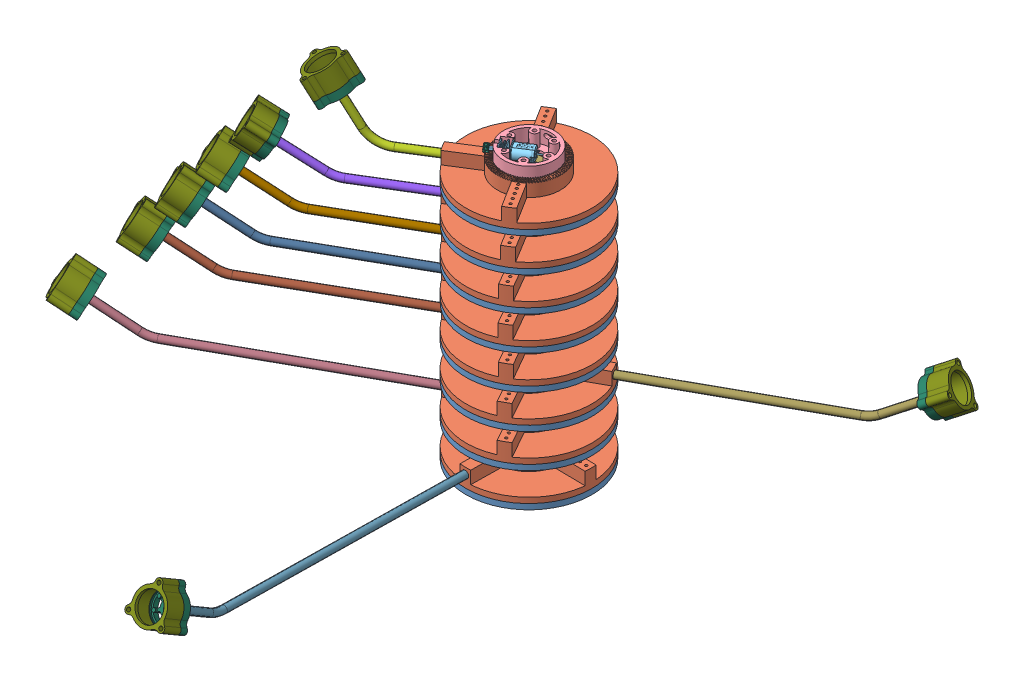
SolidWorks assembly full_assem, configuration Default. Lengths in mm.
Overall size (555.36 303.27 514.32).
88 component instances, 16 part files, 48 mates.
Components (placement in the parent):
- new_assem-1: new_assem [Default] at (2.9813 -21.7891 5.7568) size (116.84 31 116.84)
  - lower_platter-1: lower_platter [Default] at (-7.5252 -0.5831 4.7068) size (115 9 115)
  - upper_platter-1: upper_platter [Default] at (-7.5252 15.9169 4.7068) x (0.99987 0 0.016145) z (0 -1 0) size (115 115 17.53)
  - lower_platter_splitter-1: lower_platter_splitter [Default] at (-7.5252 9.4169 4.7068) x (1 0 0.000905) z (0 -1 0) size (46.67 46.67 6)
  - lower_platter_closeout-1: lower_platter_closeout [Default] at (-7.5252 12.9169 4.7068) x (1 0 0.000905) z (0 -1 0) size (46.67 46.67 16)
  - pololu_micro_motor-1: pololu_micro_motor [Default] at (-7.5351 19.4169 15.7068) x (1 0 0.000905) z (-0.000905 0 1) size (12.01 10.08 40.2)
  - lil_gear-1: lil_gear [Default] at (-7.549 19.4169 30.9948) x (1 0 0.000905) z (-0.000905 0 1) size (6.61 6.52 3.75)
- new_assem-2: new_assem [Default] at (3.2949 9.2109 14.6272) x (0.5 0 0.866025) z (-0.866025 0 0.5) size (116.84 31 116.84)
  - lower_platter-1: lower_platter [Default] at (-7.5252 -0.5831 4.7068) size (115 9 115)
  - upper_platter-1: upper_platter [Default] at (-7.5252 15.9169 4.7068) x (0.99987 0 0.016145) z (0 -1 0) size (115 115 17.53)
  - lower_platter_splitter-1: lower_platter_splitter [Default] at (-7.5252 9.4169 4.7068) x (1 0 0.000905) z (0 -1 0) size (46.67 46.67 6)
  - lower_platter_closeout-1: lower_platter_closeout [Default] at (-7.5252 12.9169 4.7068) x (1 0 0.000905) z (0 -1 0) size (46.67 46.67 16)
  - pololu_micro_motor-1: pololu_micro_motor [Default] at (-7.5351 19.4169 15.7068) x (1 0 0.000905) z (-0.000905 0 1) size (12.01 10.08 40.2)
  - lil_gear-1: lil_gear [Default] at (-7.549 19.4169 30.9948) x (1 0 0.000905) z (-0.000905 0 1) size (6.61 6.52 3.75)
- new_assem-3: new_assem [Default] at (3.35 71.2109 14.5216) x (0.511572 0 0.85924) z (-0.85924 0 0.511572) size (116.84 31 116.84)
  - lower_platter-1: lower_platter [Default] at (-7.5252 -0.5831 4.7068) size (115 9 115)
  - upper_platter-1: upper_platter [Default] at (-7.5252 15.9169 4.7068) x (0.99987 0 0.016145) z (0 -1 0) size (115 115 17.53)
  - lower_platter_splitter-1: lower_platter_splitter [Default] at (-7.5252 9.4169 4.7068) x (1 0 0.000905) z (0 -1 0) size (46.67 46.67 6)
  - lower_platter_closeout-1: lower_platter_closeout [Default] at (-7.5252 12.9169 4.7068) x (1 0 0.000905) z (0 -1 0) size (46.67 46.67 16)
  - pololu_micro_motor-1: pololu_micro_motor [Default] at (-7.5351 19.4169 15.7068) x (1 0 0.000905) z (-0.000905 0 1) size (12.01 10.08 40.2)
  - lil_gear-1: lil_gear [Default] at (-7.549 19.4169 30.9948) x (1 0 0.000905) z (-0.000905 0 1) size (6.61 6.52 3.75)
- new_assem-4: new_assem [Default] at (-12.3789 40.2109 6.2929) x (-0.499216 0 -0.866478) z (0.866478 0 -0.499216) size (116.84 31 116.84)
  - lower_platter-1: lower_platter [Default] at (-7.5252 -0.5831 4.7068) size (115 9 115)
  - upper_platter-1: upper_platter [Default] at (-7.5252 15.9169 4.7068) x (0.99987 0 0.016145) z (0 -1 0) size (115 115 17.53)
  - lower_platter_splitter-1: lower_platter_splitter [Default] at (-7.5252 9.4169 4.7068) x (1 0 0.000905) z (0 -1 0) size (46.67 46.67 6)
  - lower_platter_closeout-1: lower_platter_closeout [Default] at (-7.5252 12.9169 4.7068) x (1 0 0.000905) z (0 -1 0) size (46.67 46.67 16)
  - pololu_micro_motor-1: pololu_micro_motor [Default] at (-7.5351 19.4169 15.7068) x (1 0 0.000905) z (-0.000905 0 1) size (12.01 10.08 40.2)
  - lil_gear-1: lil_gear [Default] at (-7.549 19.4169 30.9948) x (1 0 0.000905) z (-0.000905 0 1) size (6.61 6.52 3.75)
- new_assem-5: new_assem [Default] at (3.5046 195.2109 14.2057) x (0.545217 0 0.838295) z (-0.838295 0 0.545217) size (116.84 31 116.84)
  - lower_platter-1: lower_platter [Default] at (-7.5252 -0.5831 4.7068) size (115 9 115)
  - upper_platter-1: upper_platter [Default] at (-7.5252 15.9169 4.7068) x (0.99987 0 0.016145) z (0 -1 0) size (115 115 17.53)
  - lower_platter_splitter-1: lower_platter_splitter [Default] at (-7.5252 9.4169 4.7068) x (1 0 0.000905) z (0 -1 0) size (46.67 46.67 6)
  - lower_platter_closeout-1: lower_platter_closeout [Default] at (-7.5252 12.9169 4.7068) x (1 0 0.000905) z (0 -1 0) size (46.67 46.67 16)
  - pololu_micro_motor-1: pololu_micro_motor [Default] at (-7.5351 19.4169 15.7068) x (1 0 0.000905) z (-0.000905 0 1) size (12.01 10.08 40.2)
  - lil_gear-1: lil_gear [Default] at (-7.549 19.4169 30.9948) x (1 0 0.000905) z (-0.000905 0 1) size (6.61 6.52 3.75)
- new_assem-6: new_assem [Default] at (3.365 133.2109 14.4925) x (0.514741 0 0.857346) z (-0.857346 0 0.514741) size (116.84 31 116.84)
  - lower_platter-1: lower_platter [Default] at (-7.5252 -0.5831 4.7068) size (115 9 115)
  - upper_platter-1: upper_platter [Default] at (-7.5252 15.9169 4.7068) x (0.99987 0 0.016145) z (0 -1 0) size (115 115 17.53)
  - lower_platter_splitter-1: lower_platter_splitter [Default] at (-7.5252 9.4169 4.7068) x (1 0 0.000905) z (0 -1 0) size (46.67 46.67 6)
  - lower_platter_closeout-1: lower_platter_closeout [Default] at (-7.5252 12.9169 4.7068) x (1 0 0.000905) z (0 -1 0) size (46.67 46.67 16)
  - pololu_micro_motor-1: pololu_micro_motor [Default] at (-7.5351 19.4169 15.7068) x (1 0 0.000905) z (-0.000905 0 1) size (12.01 10.08 40.2)
  - lil_gear-1: lil_gear [Default] at (-7.549 19.4169 30.9948) x (1 0 0.000905) z (-0.000905 0 1) size (6.61 6.52 3.75)
- new_assem-7: new_assem [Default] at (3.3308 102.2109 14.5589) x (0.50751 0 0.861646) z (-0.861646 0 0.50751) size (116.84 31 116.84)
  - lower_platter-1: lower_platter [Default] at (-7.5252 -0.5831 4.7068) size (115 9 115)
  - upper_platter-1: upper_platter [Default] at (-7.5252 15.9169 4.7068) x (0.99987 0 0.016145) z (0 -1 0) size (115 115 17.53)
  - lower_platter_splitter-1: lower_platter_splitter [Default] at (-7.5252 9.4169 4.7068) x (1 0 0.000905) z (0 -1 0) size (46.67 46.67 6)
  - lower_platter_closeout-1: lower_platter_closeout [Default] at (-7.5252 12.9169 4.7068) x (1 0 0.000905) z (0 -1 0) size (46.67 46.67 16)
  - pololu_micro_motor-1: pololu_micro_motor [Default] at (-7.5351 19.4169 15.7068) x (1 0 0.000905) z (-0.000905 0 1) size (12.01 10.08 40.2)
  - lil_gear-1: lil_gear [Default] at (-7.549 19.4169 30.9948) x (1 0 0.000905) z (-0.000905 0 1) size (6.61 6.52 3.75)
- new_assem-8: new_assem [Default] at (3.4595 164.2109 14.3012) x (0.535204 0 0.844723) z (-0.844723 0 0.535204) size (116.84 31 116.84)
  - lower_platter-1: lower_platter [Default] at (-7.5252 -0.5831 4.7068) size (115 9 115)
  - upper_platter-1: upper_platter [Default] at (-7.5252 15.9169 4.7068) x (0.99987 0 0.016145) z (0 -1 0) size (115 115 17.53)
  - lower_platter_splitter-1: lower_platter_splitter [Default] at (-7.5252 9.4169 4.7068) x (1 0 0.000905) z (0 -1 0) size (46.67 46.67 6)
  - lower_platter_closeout-1: lower_platter_closeout [Default] at (-7.5252 12.9169 4.7068) x (1 0 0.000905) z (0 -1 0) size (46.67 46.67 16)
  - pololu_micro_motor-1: pololu_micro_motor [Default] at (-7.5351 19.4169 15.7068) x (1 0 0.000905) z (-0.000905 0 1) size (12.01 10.08 40.2)
  - lil_gear-1: lil_gear [Default] at (-7.549 19.4169 30.9948) x (1 0 0.000905) z (-0.000905 0 1) size (6.61 6.52 3.75)
- arm0-1: arm0 [Default] at (-38.4234 205.3777 31.7281) x (0.531611 0 0.846988) z (0.846988 0 -0.531611) size (6.35 48.76 91.65)
- arm1-1: arm1 [Default] at (-38.674 174.3777 31.3234) x (0.521496 0 0.853254) z (0.853254 0 -0.521496) size (6.35 31.32 134.48)
- arm2-1: arm2 [Default] at (-39.1657 143.3777 30.4969) x (0.500832 0 0.865544) z (0.865544 0 -0.500832) size (6.35 31.32 159.88)
- arm3-1: arm3 [Default] at (-39.333 112.3777 30.2049) x (0.493533 0 0.869727) z (0.869727 0 -0.493533) size (6.35 31.32 185.28)
- arm4-1: arm4 [Default] at (-39.2394 81.3777 30.3689) x (0.497633 0 0.867388) z (0.867388 0 -0.497633) size (6.35 31.32 210.68)
- arm5-1: arm5 [Default] at (30.4331 50.3777 -8.9429) x (-0.485161 0 -0.874425) z (-0.874425 0 0.485161) size (6.35 31.32 236.08)
- arm6-1: arm6 [Default] at (-39.5033 19.3777 29.9017) x (0.485953 0 0.873985) z (0.873985 0 -0.485953) size (6.35 31.32 261.48)
- arm7-1: arm7 [Default] at (-5.1897 -11.6223 50.4584) x (0.99987 0 0.016145) z (0.016145 0 -0.99987) size (6.35 31.32 286.88)
- light_housing-1: light_housing [Default] at (-131.0667 165.473 103.0819) x (0.617031 0.771417 0.155526) z (-0.73894 0.5 0.451629) size (36.38 35.5 23.75)
  - light_housing_1-1: light_housing_1 [Default] at (13.124 21.3419 26.5612) size (36.38 35.5 7)
  - light_housing_2-1: light_housing_2 [Default] at (13.124 21.3419 47.3112) x (-1 0 0) z (0 0 -1) size (36.38 35.5 17)
- light_housing-2: light_housing [Default] at (-122.9785 211.3397 69.4133) x (0.53478 0.002163 0.844989) z (-0.423494 0.866025 0.265806) size (36.38 35.5 23.75)
  - light_housing_1-1: light_housing_1 [Default] at (13.124 21.3419 26.5612) size (36.38 35.5 7)
  - light_housing_2-1: light_housing_2 [Default] at (13.124 21.3419 47.3112) x (-1 0 0) z (0 0 -1) size (36.38 35.5 17)
- light_housing-3: light_housing [Default] at (-167.2651 143.2122 96.7592) x (-0.65725 -0.598271 -0.45836) z (-0.753206 0.5 0.427412) size (36.38 35.5 23.75)
  - light_housing_1-1: light_housing_1 [Default] at (13.124 21.3419 26.5612) size (36.38 35.5 7)
  - light_housing_2-1: light_housing_2 [Default] at (13.124 21.3419 47.3112) x (-1 0 0) z (0 0 -1) size (36.38 35.5 17)
- light_housing-4: light_housing [Default] at (-256.2752 7.9147 143.653) x (0.596799 0.266353 0.756893) z (-0.756893 0.5 0.420847) size (36.38 35.5 23.75)
  - light_housing_1-1: light_housing_1 [Default] at (13.124 21.3419 26.5612) size (36.38 35.5 7)
  - light_housing_2-1: light_housing_2 [Default] at (13.124 21.3419 47.3112) x (-1 0 0) z (0 0 -1) size (36.38 35.5 17)
- light_housing-5: light_housing [Default] at (225.3721 56.4269 -88.8401) x (0.010993 -0.653005 -0.757274) z (0.757274 0.5 -0.420162) size (36.38 35.5 23.75)
  - light_housing_1-1: light_housing_1 [Default] at (13.124 21.3419 26.5612) size (36.38 35.5 7)
  - light_housing_2-1: light_housing_2 [Default] at (13.124 21.3419 47.3112) x (-1 0 0) z (0 0 -1) size (36.38 35.5 17)
- light_housing-6: light_housing [Default] at (-213.4227 76.1178 109.2772) x (0.367319 -0.225837 0.902261) z (-0.75118 0.5 0.430963) size (36.38 35.5 23.75)
  - light_housing_1-1: light_housing_1 [Default] at (13.124 21.3419 26.5612) size (36.38 35.5 7)
  - light_housing_2-1: light_housing_2 [Default] at (13.124 21.3419 47.3112) x (-1 0 0) z (0 0 -1) size (36.38 35.5 17)
- light_housing-7: light_housing [Default] at (-22.557 -20.5345 318.8735) x (0.999895 0.003747 0.013982) z (-0.013982 0.5 0.865913) size (36.38 35.5 23.75)
  - light_housing_1-1: light_housing_1 [Default] at (13.124 21.3419 26.5612) size (36.38 35.5 7)
  - light_housing_2-1: light_housing_2 [Default] at (13.124 21.3419 47.3112) x (-1 0 0) z (0 0 -1) size (36.38 35.5 17)
- light_housing-8: light_housing [Default] at (-166.7816 132.4201 95.1575) x (0.585857 0.196204 0.786305) z (-0.749583 0.5 0.433733) size (36.38 35.5 23.75)
  - light_housing_1-1: light_housing_1 [Default] at (13.124 21.3419 26.5612) size (36.38 35.5 7)
  - light_housing_2-1: light_housing_2 [Default] at (13.124 21.3419 47.3112) x (-1 0 0) z (0 0 -1) size (36.38 35.5 17)
Mates (geometry in assembly coordinates):
- Coincident1: coincident anti-aligned: plane of new_assem-1/lower_platter_closeout-1 through (-4.5439 3.6277 10.4636) normal (0 1 0); plane of new_assem-2/lower_platter-1 through (-4.5439 3.6277 10.4636) normal (0 -1 0)
- Concentric1: concentric aligned: cylinder of new_assem-1/lower_platter-1 through (3.9986 -27.3723 25.2596) axis (0 1 0) radius 1.625; cylinder of new_assem-2/lower_platter-1 through (3.9986 3.6277 25.2596) axis (0 1 0) radius 1.625
- Concentric3: concentric aligned: cylinder of new_assem-1/lower_platter-1 through (-21.6289 -27.3723 10.4636) axis (0 1 0) radius 1.625; cylinder of new_assem-2/lower_platter-1 through (-21.6289 3.6277 10.4636) axis (0 1 0) radius 1.625
- Coincident2: coincident anti-aligned: plane of new_assem-2/lower_platter_closeout-1 through (-4.5439 34.6277 10.4636) normal (0 1 0); plane of new_assem-4/lower_platter-1 through (-4.5439 34.6277 10.4636) normal (0 -1 0)
- Concentric4: concentric anti-aligned: cylinder of new_assem-2/lower_platter_closeout-1 through (12.5411 34.6277 10.4791) axis (0 -1 0) radius 1.625; cylinder of new_assem-4/lower_platter-1 through (12.5411 34.6277 10.4791) axis (0 1 0) radius 1.625
- Concentric5: concentric aligned: cylinder of new_assem-2/upper_platter-1 through (-4.5439 13.6277 10.4636) axis (0 -1 0) radius 57.5; cylinder of new_assem-4/upper_platter-1 through (-4.5439 44.6277 10.4636) axis (0 -1 0) radius 57.5
- Coincident3: coincident anti-aligned: plane of new_assem-3/lower_platter-1 through (-4.5439 65.6277 10.4636) normal (0 -1 0); plane of new_assem-4/lower_platter_closeout-1 through (-4.5439 65.6277 10.4636) normal (0 1 0)
- Concentric6: concentric aligned: cylinder of new_assem-3/upper_platter-1 through (-4.5439 75.6277 10.4636) axis (0 -1 0) radius 57.5; cylinder of new_assem-4/upper_platter-1 through (-4.5439 44.6277 10.4636) axis (0 -1 0) radius 57.5
- Coincident4: coincident anti-aligned: plane of new_assem-3/lower_platter_closeout-1 through (-4.5439 96.6277 10.4636) normal (0 1 0); plane of new_assem-7/lower_platter-1 through (-4.5439 96.6277 10.4636) normal (0 -1 0)
- Concentric7: concentric aligned: cylinder of new_assem-3/lower_platter_closeout-1 through (-4.5439 80.6277 10.4636) axis (0 1 0) radius 13.335; cylinder of new_assem-7/lower_platter_closeout-1 through (-4.5439 111.6277 10.4636) axis (0 1 0) radius 13.335
- Coincident5: coincident anti-aligned: plane of new_assem-6/lower_platter-1 through (-4.5439 127.6277 10.4636) normal (0 -1 0); plane of new_assem-7/lower_platter_closeout-1 through (-4.5439 127.6277 10.4636) normal (0 1 0)
- Concentric8: concentric aligned: cylinder of new_assem-6/upper_platter-1 through (-4.5439 137.6277 10.4636) axis (0 -1 0) radius 57.5; cylinder of new_assem-7/upper_platter-1 through (-4.5439 106.6277 10.4636) axis (0 -1 0) radius 57.5
- Coincident6: coincident anti-aligned: plane of new_assem-6/lower_platter_closeout-1 through (-4.5439 158.6277 10.4636) normal (0 1 0); plane of new_assem-8/lower_platter-1 through (-4.5439 158.6277 10.4636) normal (0 -1 0)
- Concentric9: concentric aligned: cylinder of new_assem-6/upper_platter-1 through (-4.5439 137.6277 10.4636) axis (0 -1 0) radius 57.5; cylinder of new_assem-8/upper_platter-1 through (-4.5439 168.6277 10.4636) axis (0 -1 0) radius 57.5
- Coincident7: coincident anti-aligned: plane of new_assem-5/lower_platter-1 through (-4.5439 189.6277 10.4636) normal (0 -1 0); plane of new_assem-8/lower_platter_closeout-1 through (-4.5439 189.6277 10.4636) normal (0 1 0)
- Concentric10: concentric aligned: cylinder of new_assem-5/upper_platter-1 through (-4.5439 199.6277 10.4636) axis (0 -1 0) radius 57.5; cylinder of new_assem-8/upper_platter-1 through (-4.5439 168.6277 10.4636) axis (0 -1 0) radius 57.5
- Concentric11: concentric aligned: cylinder of new_assem-5/upper_platter-1 through (-53.2457 205.3777 41.0313) axis (0.846988 0 -0.531611) radius 3.302; cylinder of arm0-1 through (-79.7864 205.3777 57.6895) axis (0.846988 0 -0.531611) radius 3.175
- Coincident8: coincident anti-aligned: plane of new_assem-5/upper_platter-1 through (-38.4234 205.3777 31.7281) normal (-0.846988 0 0.531611); plane of arm0-1 through (-38.4234 205.3777 31.7281) normal (0.846988 0 -0.531611)
- Coincident9: coincident anti-aligned: plane of new_assem-8/upper_platter-1 through (-38.674 174.3777 31.3234) normal (-0.853254 0 0.521496); plane of arm1-1 through (-38.674 174.3777 31.3234) normal (0.853254 0 -0.521496)
- Concentric12: concentric aligned: cylinder of new_assem-8/upper_platter-1 through (-53.606 174.3777 40.4496) axis (0.853254 0 -0.521496) radius 3.302; cylinder of arm1-1 through (-108.7211 174.3777 74.1351) axis (0.853254 0 -0.521496) radius 3.175
- Concentric13: concentric aligned: cylinder of new_assem-6/upper_platter-1 through (-54.3127 143.3777 39.2614) axis (0.865544 0 -0.500832) radius 3.302; cylinder of arm2-1 through (-132.2066 143.3777 84.3334) axis (0.865544 0 -0.500832) radius 3.175
- Coincident10: coincident anti-aligned: plane of new_assem-6/upper_platter-1 through (-39.1657 143.3777 30.4969) normal (-0.865544 0 0.500832); plane of arm2-1 through (-39.1657 143.3777 30.4969) normal (0.865544 0 -0.500832)
- Concentric14: concentric aligned: cylinder of new_assem-7/upper_platter-1 through (-54.5532 112.3777 38.8417) axis (0.869727 0 -0.493533) radius 3.302; cylinder of arm3-1 through (-154.9146 112.3777 95.7925) axis (0.869727 0 -0.493533) radius 3.175
- Coincident11: coincident anti-aligned: plane of new_assem-7/upper_platter-1 through (-39.333 112.3777 30.2049) normal (-0.869727 0 0.493533); plane of arm3-1 through (-39.333 112.3777 30.2049) normal (0.869727 0 -0.493533)
- Concentric15: concentric aligned: cylinder of new_assem-3/upper_platter-1 through (-54.4187 81.3777 39.0775) axis (0.867388 0 -0.497633) radius 3.302; cylinder of arm4-1 through (-176.5417 81.3777 109.1413) axis (0.867388 0 -0.497633) radius 3.175
- Coincident12: coincident anti-aligned: plane of new_assem-3/upper_platter-1 through (-39.2394 81.3777 30.3689) normal (-0.867388 0 0.497633); plane of arm4-1 through (-39.2394 81.3777 30.3689) normal (0.867388 0 -0.497633)
- Concentric16: concentric aligned: cylinder of new_assem-4/upper_platter-1 through (45.7355 50.3777 -17.4332) axis (-0.874425 0 0.485161) radius 3.302; cylinder of arm5-1 through (191.0597 50.3777 -98.0642) axis (-0.874425 0 0.485161) radius 3.175
- Coincident13: coincident anti-aligned: plane of new_assem-4/upper_platter-1 through (30.4331 50.3777 -8.9429) normal (0.874425 0 -0.485161); plane of arm5-1 through (30.4331 50.3777 -8.9429) normal (-0.874425 0 0.485161)
- Concentric18: concentric aligned: cylinder of new_assem-2/upper_platter-1 through (-54.798 19.3777 38.4059) axis (0.873985 0 -0.485953) radius 3.302; cylinder of arm6-1 through (-222.2484 19.3777 131.5116) axis (0.873985 0 -0.485953) radius 3.175
- Coincident15: coincident anti-aligned: plane of new_assem-2/upper_platter-1 through (-39.5033 19.3777 29.9017) normal (-0.873985 0 0.485953); plane of arm6-1 through (-39.5033 19.3777 29.9017) normal (0.873985 0 -0.485953)
- Concentric19: concentric aligned: cylinder of new_assem-1/upper_platter-1 through (-5.4722 -11.6223 67.9561) axis (0.016145 0 -0.99987) radius 3.302; cylinder of arm7-1 through (-8.9756 -11.6223 284.9219) axis (0.016145 0 -0.99987) radius 3.175
- Coincident16: coincident anti-aligned: plane of new_assem-1/upper_platter-1 through (-5.1897 -11.6223 50.4584) normal (-0.016145 0 0.99987); plane of arm7-1 through (-5.1897 -11.6223 50.4584) normal (0.016145 0 -0.99987)
- Concentric20: concentric aligned: cylinder of arm7-1 through (-9.1807 -8.2193 297.6203) axis (-0.013982 0.5 0.865913) radius 3.175; cylinder of light_housing-7/light_housing_1-1 through (-9.7259 11.2777 331.3857) axis (-0.013982 0.5 0.865913) radius 3.302
- Coincident17: coincident aligned: plane of arm7-1 through (-9.7958 13.7777 335.7153) normal (-0.013982 0.5 0.865913); plane of light_housing-7/light_housing_1-1 through (-9.7958 13.7777 335.7153) normal (-0.013982 0.5 0.865913)
- Concentric21: concentric aligned: cylinder of arm6-1 through (-233.348 22.7807 137.6832) axis (-0.756893 0.5 0.420847) radius 3.175; cylinder of light_housing-4/light_housing_1-1 through (-262.8624 42.2777 154.0937) axis (-0.756893 0.5 0.420847) radius 3.302
- Coincident18: coincident aligned: plane of arm6-1 through (-266.6469 44.7777 156.198) normal (-0.756893 0.5 0.420847); plane of light_housing-4/light_housing_1-1 through (-266.6469 44.7777 156.198) normal (-0.756893 0.5 0.420847)
- Concentric22: concentric aligned: cylinder of arm5-1 through (202.1649 53.7807 -104.2257) axis (0.757274 0.5 -0.420162) radius 3.175; cylinder of light_housing-5/light_housing_1-1 through (231.6941 73.2777 -120.6096) axis (0.757274 0.5 -0.420162) radius 3.302
- Coincident19: coincident aligned: plane of arm5-1 through (235.4805 75.7777 -122.7104) normal (0.757274 0.5 -0.420162); plane of light_housing-5/light_housing_1-1 through (235.4805 75.7777 -122.7104) normal (0.757274 0.5 -0.420162)
- Concentric23: concentric aligned: cylinder of arm4-1 through (-187.5576 84.7807 115.4612) axis (-0.75118 0.5 0.430963) radius 3.175; cylinder of light_housing-6/light_housing_1-1 through (-216.8491 104.2777 132.2662) axis (-0.75118 0.5 0.430963) radius 3.302
- Coincident20: coincident aligned: plane of arm4-1 through (-220.605 106.7777 134.4211) normal (-0.75118 0.5 0.430963); plane of light_housing-6/light_housing_1-1 through (-220.605 106.7777 134.4211) normal (-0.75118 0.5 0.430963)
- Concentric24: concentric aligned: cylinder of arm3-1 through (-165.9601 115.7807 102.0604) axis (-0.753206 0.5 0.427412) radius 3.175; cylinder of light_housing-3/light_housing_1-1 through (-195.3307 135.2777 118.7269) axis (-0.753206 0.5 0.427412) radius 3.302
- Coincident21: coincident aligned: plane of arm3-1 through (-199.0967 137.7777 120.864) normal (-0.753206 0.5 0.427412); plane of light_housing-3/light_housing_1-1 through (-199.0967 137.7777 120.864) normal (-0.753206 0.5 0.427412)
- Concentric25: concentric aligned: cylinder of arm2-1 through (-143.199 146.7807 90.694) axis (-0.749583 0.5 0.433733) radius 3.175; cylinder of light_housing-8/light_housing_1-1 through (-172.4283 166.2777 107.607) axis (-0.749583 0.5 0.433733) radius 3.302
- Coincident22: coincident aligned: plane of arm2-1 through (-176.1762 168.7777 109.7757) normal (-0.749583 0.5 0.433733); plane of light_housing-8/light_housing_1-1 through (-176.1762 168.7777 109.7757) normal (-0.749583 0.5 0.433733)
- Concentric26: concentric aligned: cylinder of arm1-1 through (-119.5575 177.7807 80.7581) axis (-0.73894 0.5 0.451629) radius 3.175; cylinder of light_housing-1/light_housing_1-1 through (-148.3717 197.2777 98.369) axis (-0.73894 0.5 0.451629) radius 3.302
- Coincident23: coincident aligned: plane of arm1-1 through (-152.0664 199.7777 100.6271) normal (-0.73894 0.5 0.451629); plane of light_housing-1/light_housing_1-1 through (-152.0664 199.7777 100.6271) normal (-0.73894 0.5 0.451629)
- Concentric27: concentric aligned: cylinder of arm0-1 through (-98.4176 218.0777 69.3833) axis (-0.423494 0.866025 0.265806) radius 3.175; cylinder of light_housing-2/light_housing_1-1 through (-111.6032 245.0417 77.6593) axis (-0.423494 0.866025 0.265806) radius 3.302
- Coincident24: coincident aligned: plane of arm0-1 through (-113.7207 249.3718 78.9883) normal (-0.423494 0.866025 0.265806); plane of light_housing-2/light_housing_1-1 through (-113.7207 249.3718 78.9883) normal (-0.423494 0.866025 0.265806)
